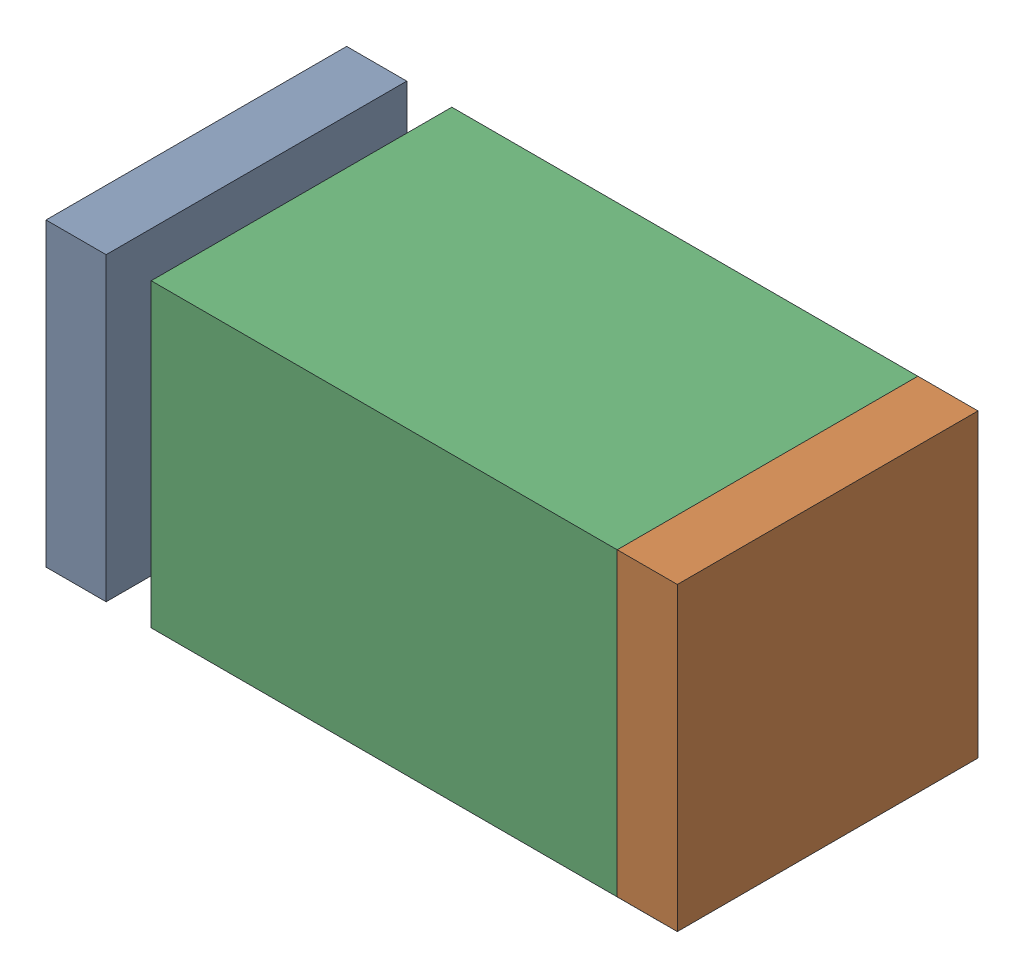
SolidWorks assembly C22, configuration Default. Lengths in mm.
Overall size (1.05 0.5 0.5).
6 component instances, 2 part files, 0 mates.
Components (placement in the parent):
- 810156080-1: 810156080 [Default] at (130.5 24.85 0) size (0.1 0.5 0.5)
  - Extruded_5-1: Extruded_5 [Default] at origin size (0.1 0.5 0.5)
- 810156080-2: 810156080 [Default] at (131.45 24.85 0) size (0.1 0.5 0.5)
  - Extruded_5-1: Extruded_5 [Default] at origin size (0.1 0.5 0.5)
- 810156208-1: 810156208 [Default] at (131.0499 24.8499 0) size (0.85 0.5 0.5)
  - Extruded_17-1: Extruded_17 [Default] at origin size (0.85 0.5 0.5)
